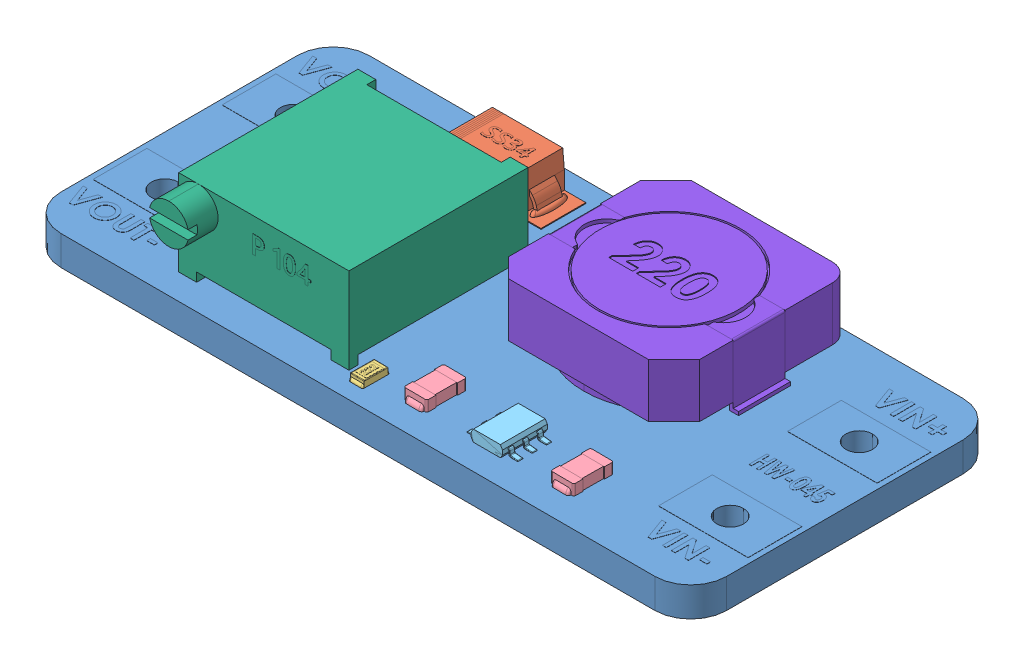
SolidWorks assembly MT3608 Converter.STEP, configuration Default. Lengths in mm.
Overall size (37.15 7.3 17.43).
11 component instances, 8 part files, 0 mates.
Components (placement in the parent):
- MT3608 Converter PCB.STEP-1: MT3608 Converter PCB.STEP [Default] at origin size (37.15 1.67 17.2)
- smdS537diode.STEP-1: smdS537diode.STEP [Default] at (-6.6188 1.7 -6.2378) size (6.5 2.06 2.5)
- tinySMDResistor222.STEP-1: tinySMDResistor222.STEP [Default] at (-1.0169 1.5323 6.9503) x (0.008727 0 -0.999962) z (0.999962 0 0.008727) size (1.52 0.38 0.79)
- smdceramiccapacitorbrown.STEP-1: smdceramiccapacitorbrown.STEP [Default] at (1.6628 1.65 5.9475) x (0.008727 0 -0.999962) z (0.999962 0 0.008727) size (2.52 0.61 1.3)
- tinysmdChip6pin.STEP-1: tinysmdChip6pin.STEP [Default] at (5.7797 2.0883 4.6814) size (2.85 0.65 2.5)
- smdceramiccapacitorbrown.STEP-2: smdceramiccapacitorbrown.STEP [Default] at (9.8138 1.65 5.9026) x (0.008727 0 -0.999962) z (0.999962 0 0.008727) size (2.52 0.61 1.3)
- HorizonatalTrimmerP104.STEP-1: HorizonatalTrimmerP104.STEP [Default] at (-6.6754 6.45 2.4252) x (1 0 0) z (0 -1 0) size (9.5 11.65 7.3)
- solder.STEP-1: solder.STEP [Default] at (-4.1552 0 3.4301) x (-0.837169 0 -0.546944) z (-0.546944 0 0.837169) size (1.17 0.65 1.17)
- solder.STEP-2: solder.STEP [Default] at (-9.184 0 3.4301) x (-0.837169 0 -0.546944) z (-0.546944 0 0.837169) size (1.17 0.65 1.17)
- solder.STEP-3: solder.STEP [Default] at (-6.6776 0 5.4144) x (-0.837169 0 -0.546944) z (-0.546944 0 0.837169) size (1.17 0.65 1.17)
- smbInductor220.STEP-1: smbInductor220.STEP [Default] at (5.6448 2.15 -2.551) size (10.9 3.5 9.85)
